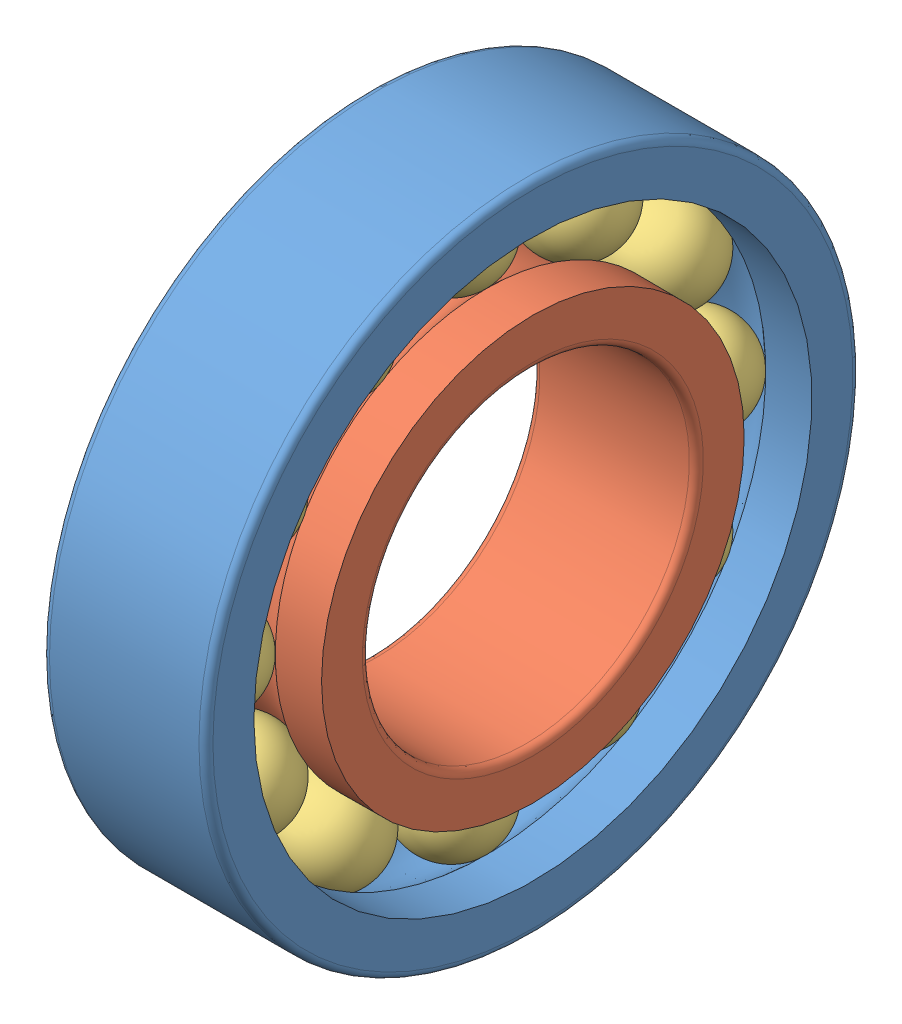
SolidWorks assembly Assem1, configuration Default. Lengths in mm.
Overall size (4.55 14 14).
14 component instances, 3 part files, 0 mates.
Components (placement in the parent):
- 687_Outer_Ring-1: 687_Outer_Ring [Default] at origin size (3.5 14 14)
- 687_Inner_Ring-1: 687_Inner_Ring [Default] x (1 0 0) z (0 -1 0) size (3.5 9.05 9.05)
- 687_Ball-1: 687_Ball [Default] at (1.75 0 5.25) x (1 0 0) z (0 -1 0) size (2.1 2.1 2.1)
- 687_Ball-2: 687_Ball [Default] at (1.75 -2.625 4.5466) x (1 0 0) z (0 -1 0) size (2.1 2.1 2.1)
- 687_Ball-3: 687_Ball [Default] at (1.75 -4.5466 2.625) x (1 0 0) z (0 -1 0) size (2.1 2.1 2.1)
- 687_Ball-4: 687_Ball [Default] at (1.75 -5.25 0) x (1 0 0) z (0 -1 0) size (2.1 2.1 2.1)
- 687_Ball-5: 687_Ball [Default] at (1.75 -4.5466 -2.625) x (1 0 0) z (0 -1 0) size (2.1 2.1 2.1)
- 687_Ball-6: 687_Ball [Default] at (1.75 -2.625 -4.5466) x (1 0 0) z (0 -1 0) size (2.1 2.1 2.1)
- 687_Ball-7: 687_Ball [Default] at (1.75 0 -5.25) x (1 0 0) z (0 -1 0) size (2.1 2.1 2.1)
- 687_Ball-8: 687_Ball [Default] at (1.75 2.625 -4.5466) x (1 0 0) z (0 -1 0) size (2.1 2.1 2.1)
- 687_Ball-9: 687_Ball [Default] at (1.75 4.5466 -2.625) x (1 0 0) z (0 -1 0) size (2.1 2.1 2.1)
- 687_Ball-10: 687_Ball [Default] at (1.75 5.25 0) x (1 0 0) z (0 -1 0) size (2.1 2.1 2.1)
- 687_Ball-11: 687_Ball [Default] at (1.75 4.5466 2.625) x (1 0 0) z (0 -1 0) size (2.1 2.1 2.1)
- 687_Ball-12: 687_Ball [Default] at (1.75 2.625 4.5466) x (1 0 0) z (0 -1 0) size (2.1 2.1 2.1)
